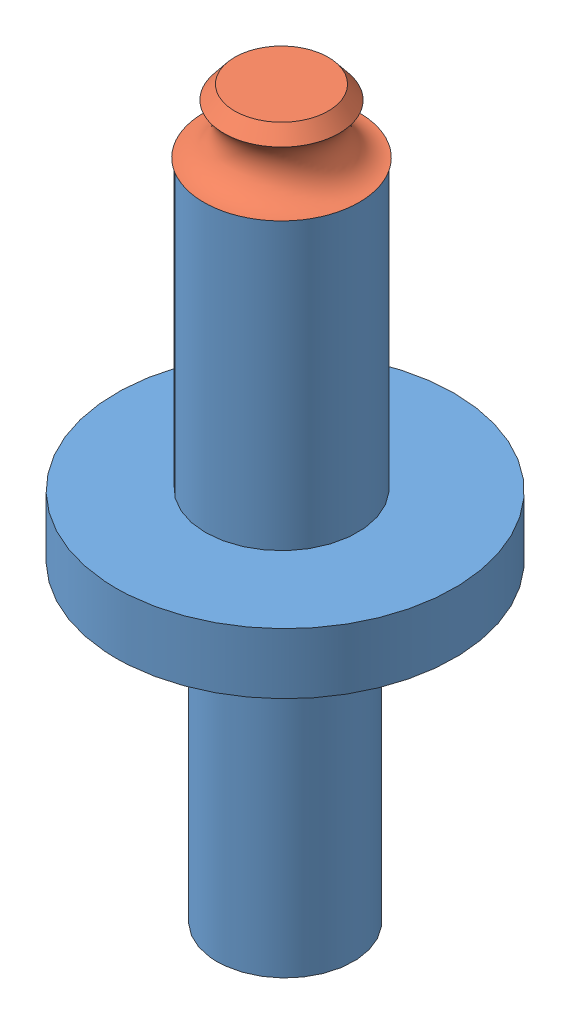
SolidWorks assembly Assem1, configuration Default. Lengths in mm.
Overall size (10.31 22.08 10.31).
2 component instances, 2 part files, 1 mates.
Components (placement in the parent):
- Part1-1: Part1 [Default] at (10.146 0.534 14.121) size (10.31 20.13 10.31)
- Part2-1: Part2 [Default] at (10.0349 20.6774 14.121) x (0.998883 0 -0.047253) z (0.047253 0 0.998883) size (4.73 1.94 4.73)
Mates (geometry in assembly coordinates):
- Concentric1: concentric anti-aligned: circle of Part1-1; circle of Part2-1
